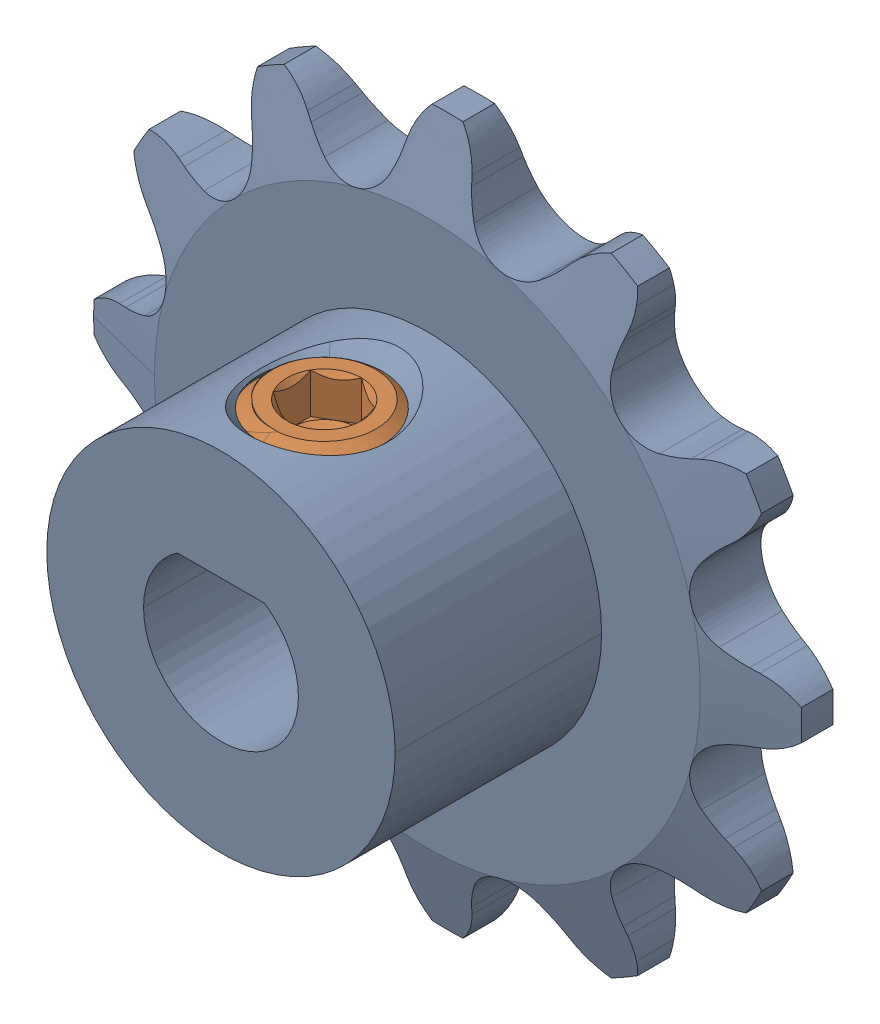
SolidWorks assembly 3304-1006-0012 assembly, configuration Default. Lengths in mm.
Overall size (27.43 27.43 10.94).
3 component instances, 2 part files, 0 mates.
Components (placement in the parent):
- 3304-1006-0012 assembly.STEP-1: 3304-1006-0012 assembly.STEP [Default] at origin size (27.43 27.43 10.94)
  - 3304-1006-0012.STEP-1: 3304-1006-0012.STEP [Default] at (-36.7101 -2.0252 16.7473) size (27.43 27.43 10.94)
  - 2806-0005-0004_91390A117.STEP-1: 2806-0005-0004_91390A117.STEP [Default] at (-36.7101 2.8664 22.1443) x (1 0 0) z (0 1 0) size (5.01 5.01 4.01)
